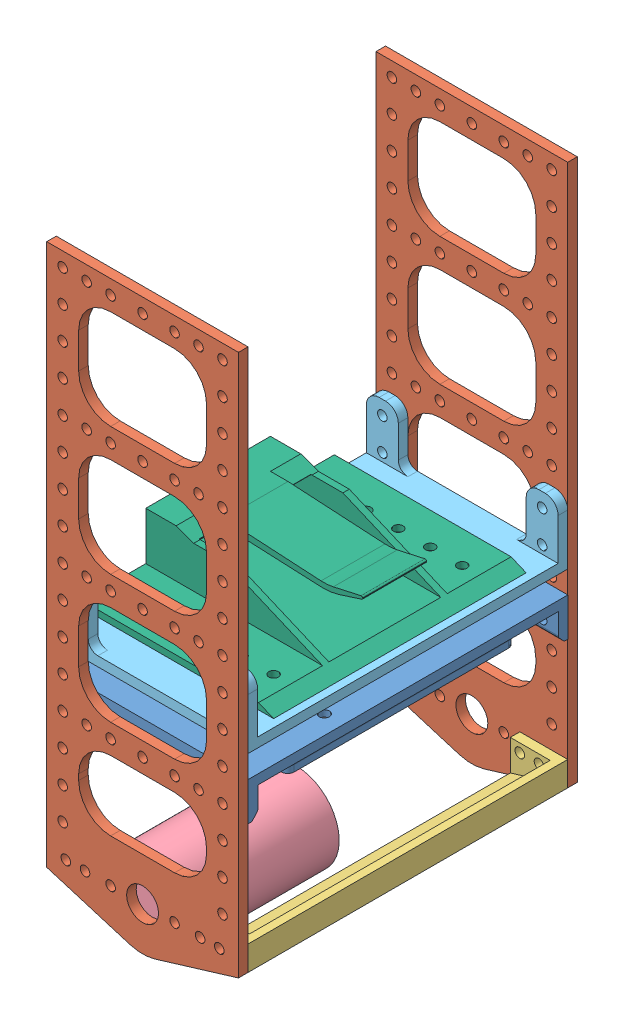
SolidWorks assembly Assembly, configuration Default. Lengths in mm.
Overall size (62.51 178 106).
7 component instances, 6 part files, 17 mates.
Components (placement in the parent):
- Arduino_mount_reviewed-1: Arduino_mount_reviewed [Default] at (-105.8732 24.0252 41.5836) size (60 12 100)
- vertical_panel-1: vertical_panel [Default] at (-106.367 -22.0635 91.5836) size (60 178 3)
- vertical_panel-2: vertical_panel [Default] at (-106.367 -22.0635 -11.4164) size (60 178 3)
- struct_lower-1: struct_lower [Default] at (-142.5015 -21.0711 91.5836) x (-1 0 0) z (0 -1 0) size (14.97 100 12.25)
- motor-1: motor [Default] at (-105.9135 -20.2774 46.5836) size (27 27 45)
- battery_mount_mount-1: battery_mount_mount [Default] at (-105.9135 34.0262 41.5836) x (0 0 -1) z (1 0 0) size (100 20 60)
- battery_mount-1: battery_mount [Default] at (-138.3796 39.0262 59.1212) x (0 0 -1) z (0 -1 0) size (79 60 17.48)
Mates (geometry in assembly coordinates):
- Concentric1: concentric aligned: cylinder of Arduino_mount_reviewed-1 through (-105.9135 19.518 91.5836) axis (0 0 -1) radius 1.5; cylinder of vertical_panel-1 through (-105.9135 19.518 94.5836) axis (0 0 -1) radius 1.5
- Coincident1: coincident anti-aligned: plane of Arduino_mount_reviewed-1 through (-105.8732 27.0252 91.5836) normal (0 0 1); plane of vertical_panel-1 through (-106.367 -22.0635 91.5836) normal (0 0 -1)
- Concentric2: concentric aligned: cylinder of Arduino_mount_reviewed-1 through (-130.9135 19.518 91.5836) axis (0 0 -1) radius 1.5; cylinder of vertical_panel-1 through (-130.9135 19.518 94.5836) axis (0 0 -1) radius 1.5
- Concentric3: concentric anti-aligned: cylinder of Arduino_mount_reviewed-1 through (-105.9135 19.518 -8.4164) axis (0 0 1) radius 1.5; cylinder of vertical_panel-2 through (-105.9135 19.518 -8.4164) axis (0 0 -1) radius 1.5
- Coincident2: coincident anti-aligned: plane of Arduino_mount_reviewed-1 through (-105.8732 27.0252 -8.4164) normal (0 0 -1); plane of vertical_panel-2 through (-106.367 -22.0635 -8.4164) normal (0 0 1)
- Concentric4: concentric anti-aligned: cylinder of Arduino_mount_reviewed-1 through (-130.9135 19.518 -8.4164) axis (0 0 1) radius 1.5; cylinder of vertical_panel-2 through (-130.9135 19.518 -8.4164) axis (0 0 -1) radius 1.5
- Coincident10: coincident anti-aligned: plane of vertical_panel-1 through (-106.367 -22.0635 91.5836) normal (0 0 -1); plane of struct_lower-1 through (-142.5015 -21.0711 91.5836) normal (0 0 1)
- Concentric10: concentric anti-aligned: cylinder of vertical_panel-1 through (-81.9135 -20.2774 94.5836) axis (0 0 -1) radius 1.5; cylinder of struct_lower-1 through (-81.9135 -20.2774 88.5836) axis (0 0 1) radius 1.5
- Concentric11: concentric anti-aligned: cylinder of vertical_panel-1 through (-87.9135 -20.2774 94.5836) axis (0 0 -1) radius 1.5; cylinder of struct_lower-1 through (-87.9135 -20.2774 88.5836) axis (0 0 1) radius 1.5
- Coincident11: coincident aligned: circle of vertical_panel-1; plane of motor-1 through (-105.9135 -20.2774 91.5836) normal (0 0 1)
- Concentric12: concentric aligned: circle of vertical_panel-1; circle of motor-1
- Coincident12: coincident aligned: cylinder of vertical_panel-1 through (-80.9135 49.5862 94.5836) axis (0 0 -1) radius 1.5; circle of battery_mount_mount-1
- Concentric14: concentric aligned: cylinder of vertical_panel-2 through (-130.9135 49.5862 -8.4164) axis (0 0 -1) radius 1.5; cylinder of battery_mount_mount-1 through (-130.9135 49.5862 -5.4164) axis (0 0 -1) radius 1.5
- Coincident13: coincident anti-aligned: plane of vertical_panel-2 through (-106.367 -22.0635 -8.4164) normal (0 0 1); plane of battery_mount_mount-1 through (-105.9135 37.0262 -8.4164) normal (0 0 -1)
- Coincident14: coincident: plane of battery_mount_mount-1 through (-105.9135 37.0262 41.5836) normal (0 1 0); plane of battery_mount-1 through (-136.3796 37.0262 59.1212) normal (0 -1 0)
- Concentric19: concentric: cylinder of battery_mount_mount-1 through (-88.3796 37.0262 12.1212) axis (0 -1 0) radius 1.5; cylinder of battery_mount-1 through (-88.3796 37.0262 12.1212) axis (0 1 0) radius 1.5
- Concentric20: concentric anti-aligned: cylinder of battery_mount_mount-1 through (-88.3796 37.0262 71.1212) axis (0 -1 0) radius 1.5; cylinder of battery_mount-1 through (-88.3796 37.0262 71.1212) axis (0 1 0) radius 1.5
